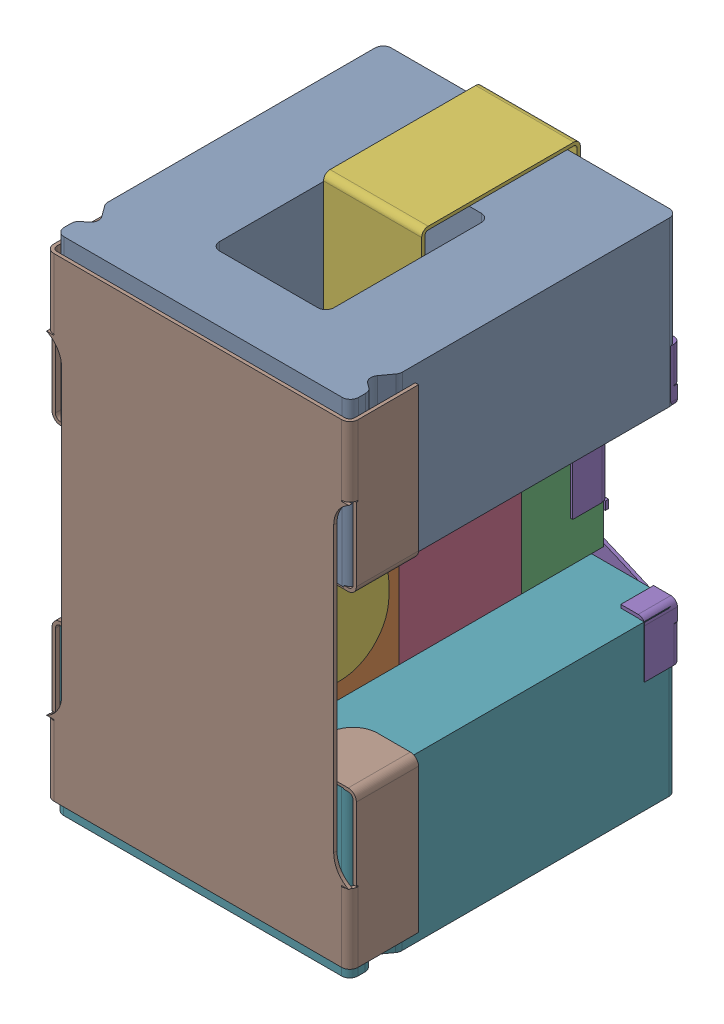
SolidWorks assembly U300_2PCB, configuration Default. Lengths in mm.
Overall size (1.86 3.21 2.06).
7 component instances, 5 part files, 0 mates.
Components (placement in the parent):
- User_Library-filterassy-1-1: User_Library-filterassy-1 [Default] at (160.4939 95.8124 0.0128) x (0 -1 0) z (-1 0 0) size (3.21 2.06 1.86)
  - User_Library-filterassy-1_ferrite001_1-1: User_Library-filterassy-1_ferrite001_1 [Default] at (-1.7182 1.0098 -0.0449) x (0 0 -1) z (1 0 0) size (1.8 2 1)
  - User_Library-filterassy-1_0603cap_1-1: User_Library-filterassy-1_0603cap_1 [Default] at (-0.2006 0.895 0.4524) x (0 -1 0) z (1 0 0) size (1.75 0.9 0.95)
  - User_Library-filterassy-1_bottom_bracketSLDPRT_1-1: User_Library-filterassy-1_bottom_bracketSLDPRT_1 [Default] at origin size (1.7 0.22 1.8)
  - User_Library-filterassy-1_cap_top_hat_1-1: User_Library-filterassy-1_cap_top_hat_1 [Default] at (-0.1923 1.79 0.0135) x (-1 0 0) z (0 0 1) size (3.21 1.79 1)
  - User_Library-filterassy-1_ferrite001_1-2: User_Library-filterassy-1_ferrite001_1 [Default] at (0.3475 1.0098 -0.0411) x (0 0 -1) z (1 0 0) size (1.8 2 1)
  - User_Library-filterassy-1_top_1-1: User_Library-filterassy-1_top_1 [Default] at (-0.1875 2.0589 -0.0063) x (-1 0 0) z (0 0 1) size (2.9 0.42 1.86)
